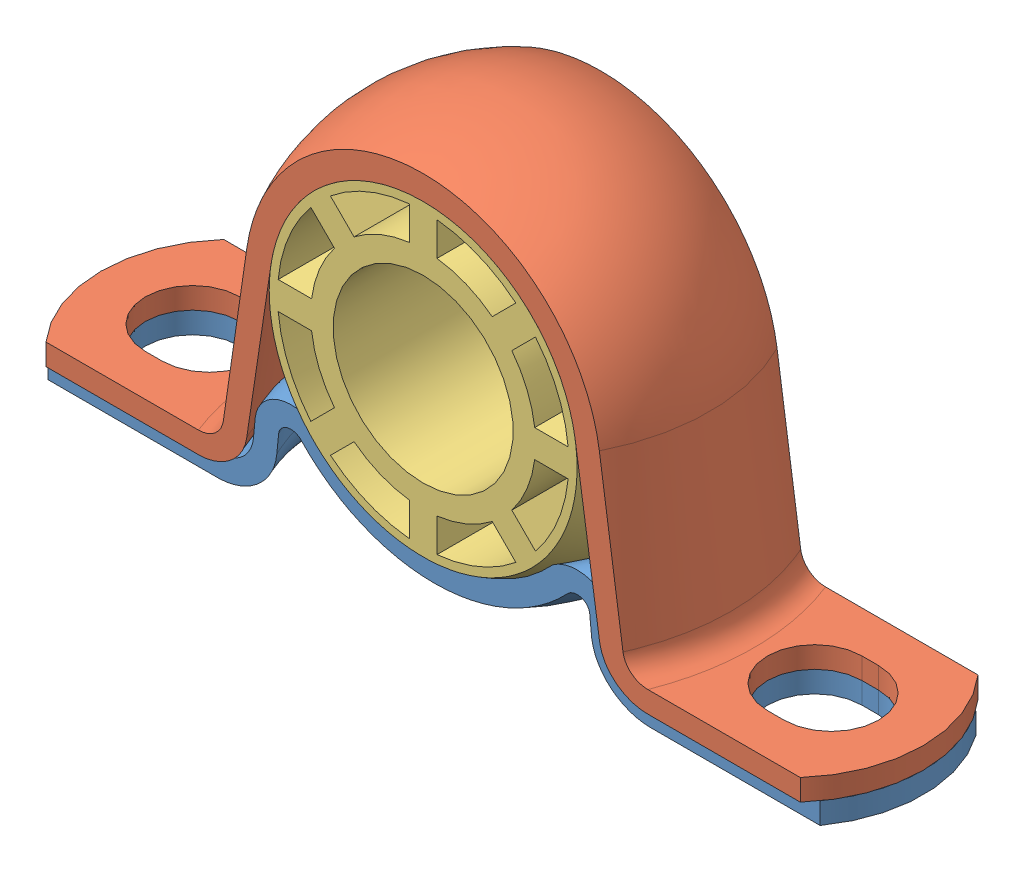
SolidWorks assembly Pillow Block Bearing, configuration Default. Lengths in mm.
Overall size (58.75 28.72 27.42).
3 component instances, 3 part files, 0 mates.
Components (placement in the parent):
- Pillow Block Bearing_Base-1: Pillow Block Bearing_Base [Default] at origin size (58.75 8.17 17.61)
- Pillow Block Bearing_Strap-1: Pillow Block Bearing_Strap [Default] at (0 1.524 0) size (58.75 27.15 27.42)
- Pillow Block Bearing_N8-1: Pillow Block Bearing_N8 [Default] at (0 14.224 0) x (1 0 0) z (0 1 0) size (25.39 25.4 25.63)
